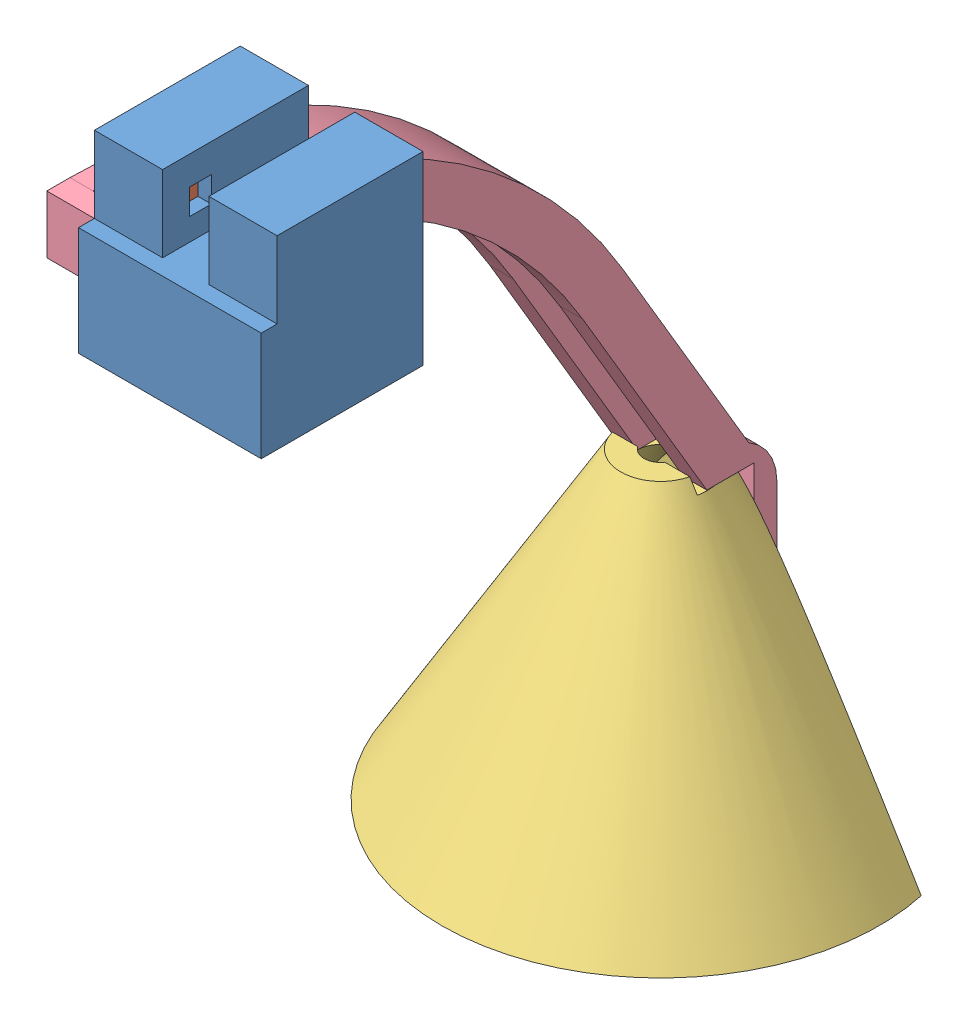
SolidWorks assembly funnelAssem_v2, configuration Default. Lengths in mm.
Overall size (60 134.54 109.96).
4 component instances, 4 part files, 8 mates.
Components (placement in the parent):
- photoInterrupterCase-1: photoInterrupterCase [Default] at (11.4161 -29.874 5.6436) size (25.05 25.4 22.18)
- photoInterruptor_outline-1: photoInterruptor_outline [Default] at (11.4161 -19.849 12.4686) size (18.6 15.2 5)
- funnelCone_v2-1: funnelCone_v2 [Default] at (-1.2839 -122.899 -62.1414) x (1 0 0) z (0 0 -1) size (60 74.98 60)
- funnelTrack_v2-1: funnelTrack_v2 [Default] at (-1.2839 -122.899 -62.1414) x (1 0 0) z (0 0 -1) size (60 124.06 107.78)
Mates (geometry in assembly coordinates):
- Coincident1: coincident: plane of photoInterrupterCase-1 through (11.4161 -29.874 12.4686) normal (0 0 -1); plane of photoInterruptor_outline-1 through (11.4161 -19.849 12.4686) normal (0 0 1)
- Coincident2: coincident: plane of photoInterrupterCase-1 through (11.4161 -7.649 12.4686) normal (0 -1 0); plane of photoInterruptor_outline-1 through (16.4161 -7.649 7.4686) normal (0 1 0)
- Coincident3: coincident: plane of photoInterrupterCase-1 through (16.4161 -29.874 12.4686) normal (1 0 0); plane of photoInterruptor_outline-1 through (16.4161 -19.849 7.4686) normal (-1 0 0)
- Coincident14: coincident: plane of photoInterrupterCase-1 through (2.0661 -4.474 15.6436) normal (0 0 1); plane of funnelTrack_v2-1 through (5.0661 -22.8865 15.6436) normal (0 0 1)
- Coincident15: coincident: line of photoInterrupterCase-1 through (14.5911 -14.949 15.6436) axis (1 0 0); line of funnelTrack_v2-1 through (5.0661 -14.949 15.6436) axis (-1 0 0)
- Coincident16: coincident: plane of photoInterrupterCase-1 through (14.5911 -29.874 15.6436) normal (-1 0 0); plane of funnelTrack_v2-1 through (14.5911 22.3833 -4.3564) normal (1 0 0)
- Coincident17: coincident: circle of funnelCone_v2-1; circle of funnelTrack_v2-1
- Coincident18: coincident: plane of funnelCone_v2-1 through (38.7444 -83.004 -68.5814) normal (0 0 -1); plane of funnelTrack_v2-1 through (47.8747 -83.004 -68.5814) normal (0 0 1)
